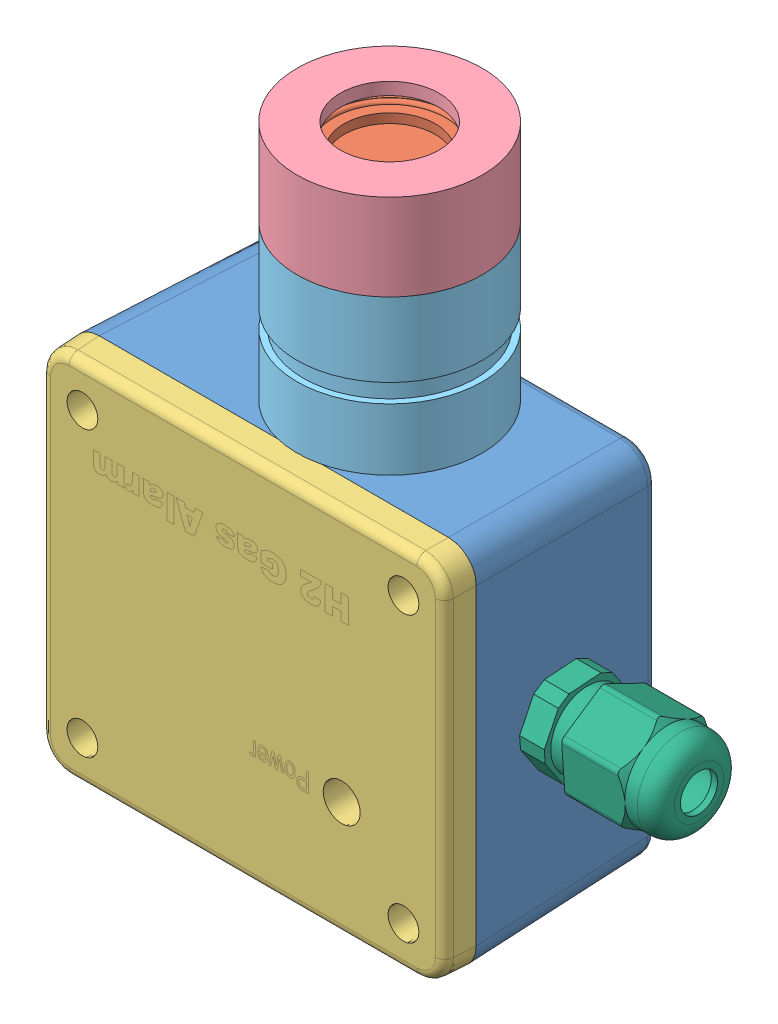
SolidWorks assembly 装配体1, configuration 默认. Lengths in mm.
Overall size (1655.74 254.2 37.77).
239 component instances, 39 part files, 20 mates.
Components (placement in the parent):
- 壳体-1: 壳体 [默认] at (-8.2267 -8.8655 -15.75) size (65.57 59.57 31.5)
- 气体传感器-1: 气体传感器 [默认] at (28.2733 85.2184 -0.0196) x (0.230368 0 0.973104) z (0 -1 0) size (23.5 23.5 30)
- 上盖-1: 上盖 [默认] at (-9.0112 49.9189 19.25) x (1 0 0) z (0 0 -1) size (1633.92 254.2 5.13)
- 传感器顶盖-1: 传感器顶盖 [默认] at (28.2733 89.2184 -0.0196) x (-0.96269 0 -0.270608) z (-0.270608 0 0.96269) size (30 14 30)
- 传感器外壳-1: 传感器外壳 [默认] at (28.2733 80.2184 -0.0196) x (-0.983101 0 -0.183066) z (-0.183066 0 0.983101) size (30 43 30)
- M12-1: M12 [默认] at (73.3763 20.1345 -0.0196) x (0 0.997541 0.070081) z (-1 0 0) size (15.86 14 27)
- 六角螺柱-1: 六角螺柱 [默认] at (21.8837 58.3069 5.887) x (-0.923728 0 0.383049) z (0 -1 0) size (3.46 3 8)
- 六角螺柱-2: 六角螺柱 [默认] at (36.8926 58.3069 -1.944) x (-0.932012 0 0.362427) z (0 -1 0) size (3.46 3 8)
- 六角螺柱-3: 六角螺柱 [默认] at (19.9913 58.3069 -2.9118) x (-0.923728 0 0.383049) z (0 -1 0) size (3.46 3 8)
- 传感器插座板-2: 传感器插座板 [Default] at (28.3871 58.7184 -0.1146) x (-0.21027 0 -0.977643) z (0 1 0) size (23.52 23.52 6.2)
  - JP2.step-1: JP2.step [Default] at origin size (15.8 14.1 6.2)
    - __________.step-1: __________.step [Default] at (-6.3999 3.7001 0) size (3 3 6.2)
    - __________.step-2: __________.step [Default] at (6.4001 -3.7 0) size (3 3 6.2)
    - __________.step-3: __________.step [Default] at (-6.3999 -3.6999 0) size (3 3 6.2)
    - __________.step-4: __________.step [Default] at (6.4001 3.7001 0) size (3 3 6.2)
    - __________.step-5: __________.step [Default] at (0.0001 7.4001 0) size (3 3 6.2)
  - Board^传感器插座板-1: Board^传感器插座板 [Default] at (0 0 -0.4115) size (23.52 23.52 0.41) (virtual)
- 传感器电路板-1: 传感器电路板 [默认] at (25.0182 19.4047 -5.8385) x (-1 -0.00061 0) z (0 0 1) size (52.02 47.02 9.61)
  - 传感器电路板.step-1: 传感器电路板.step [Default] at origin size (52.02 47.02 9.61)
    - U3.step-1: U3.step [Default] at origin size (8.7 6.01 1.9)
      - SOP14.step-1: SOP14.step [Default] at (4.699 -2.54 0) x (0 1 0) z (0 0 1) size (6.01 8.7 1.9)
        - LOGO__0.25.step-1: LOGO__0.25.step [Default] at (0.0116 0 0.095) x (0 -1 0) z (0 0 -1) size (0.75 0.87 0.01)
        - SOP14_____.step-1: SOP14_____.step [Default] at origin size (3.6 8.7 1.8)
        - ____1.8_______.step-1: ____1.8_______.step [Default] at (1.8 3.84 1) x (0 1 0) z (0 0 1) size (0.5 1.2 1.1)
        - ____1.8_______.step-2: ____1.8_______.step [Default] at (1.8 2.57 1) x (0 1 0) z (0 0 1) size (0.5 1.2 1.1)
        - ____1.8_______.step-3: ____1.8_______.step [Default] at (1.8 1.3 1) x (0 1 0) z (0 0 1) size (0.5 1.2 1.1)
        - ____1.8_______.step-4: ____1.8_______.step [Default] at (1.8 0.03 1) x (0 1 0) z (0 0 1) size (0.5 1.2 1.1)
        - ____1.8_______.step-5: ____1.8_______.step [Default] at (1.8 -1.24 1) x (0 1 0) z (0 0 1) size (0.5 1.2 1.1)
        - ____1.8_______.step-6: ____1.8_______.step [Default] at (1.8 -2.51 1) x (0 1 0) z (0 0 1) size (0.5 1.2 1.1)
        - ____1.8_______.step-7: ____1.8_______.step [Default] at (1.8 -3.78 1) x (0 1 0) z (0 0 1) size (0.5 1.2 1.1)
        - ____1.8_______.step-8: ____1.8_______.step [Default] at (-1.8 3.84 1) x (0 -1 0) z (0 0 1) size (0.5 1.2 1.1)
        - ____1.8_______.step-9: ____1.8_______.step [Default] at (-1.8 2.57 1) x (0 -1 0) z (0 0 1) size (0.5 1.2 1.1)
        - ____1.8_______.step-10: ____1.8_______.step [Default] at (-1.8 1.3 1) x (0 -1 0) z (0 0 1) size (0.5 1.2 1.1)
        - ____1.8_______.step-11: ____1.8_______.step [Default] at (-1.8 0.03 1) x (0 -1 0) z (0 0 1) size (0.5 1.2 1.1)
        - ____1.8_______.step-12: ____1.8_______.step [Default] at (-1.8 -1.24 1) x (0 -1 0) z (0 0 1) size (0.5 1.2 1.1)
        - ____1.8_______.step-13: ____1.8_______.step [Default] at (-1.8 -2.51 1) x (0 -1 0) z (0 0 1) size (0.5 1.2 1.1)
        - ____1.8_______.step-14: ____1.8_______.step [Default] at (-1.8 -3.78 1) x (0 -1 0) z (0 0 1) size (0.5 1.2 1.1)
    - U2.step-1: U2.step [Default] at origin size (2.81 3 1.18)
      - SOT23-6.step-1: SOT23-6.step [Default] at (-12.954 7.493 0) x (0 -1 0) z (0 0 1) size (3 2.81 1.18)
        - SOT23-5and6_____.step-1: SOT23-5and6_____.step [Default] at (-0.95 -0.8 0.675) x (-1 0 0) z (0 0 1) size (0.4 0.6 0.78)
        - SOT23-5and6_____.step-2: SOT23-5and6_____.step [Default] at (0 -0.8 0.675) x (-1 0 0) z (0 0 1) size (0.4 0.6 0.78)
        - SOT23-5and6_____.step-3: SOT23-5and6_____.step [Default] at (0.95 -0.8 0.675) x (-1 0 0) z (0 0 1) size (0.4 0.6 0.78)
        - SOT23-5and6_____.step-4: SOT23-5and6_____.step [Default] at (-0.95 0.8 0.675) size (0.4 0.6 0.78)
        - SOT23-5and6_____.step-5: SOT23-5and6_____.step [Default] at (0.95 0.8 0.675) size (0.4 0.6 0.78)
        - LOGO__0.15.step-1: LOGO__0.15.step [Default] at (0 -0.0167 0.0485) x (-1 0 0) z (0 0 -1) size (0.45 0.52 0)
        - SOT23-6-0.step-1: SOT23-6-0.step [Default] at origin size (3 1.6 1.1)
        - SOT23-5and6_____.step-6: SOT23-5and6_____.step [Default] at (0 0.8 0.675) size (0.4 0.6 0.78)
    - U1.step-1: U1.step [Default] at origin size (3 2.81 1.18)
      - SOT23-6.step-1: SOT23-6.step [Default] at (-13.589 -8.636 0) x (-1 0 0) z (0 0 1) size (3 2.81 1.18)
        - SOT23-5and6_____.step-1: SOT23-5and6_____.step [Default] at (-0.95 -0.8 0.675) x (-1 0 0) z (0 0 1) size (0.4 0.6 0.78)
        - SOT23-5and6_____.step-2: SOT23-5and6_____.step [Default] at (0 -0.8 0.675) x (-1 0 0) z (0 0 1) size (0.4 0.6 0.78)
        - SOT23-5and6_____.step-3: SOT23-5and6_____.step [Default] at (0.95 -0.8 0.675) x (-1 0 0) z (0 0 1) size (0.4 0.6 0.78)
        - SOT23-5and6_____.step-4: SOT23-5and6_____.step [Default] at (-0.95 0.8 0.675) size (0.4 0.6 0.78)
        - SOT23-5and6_____.step-5: SOT23-5and6_____.step [Default] at (0.95 0.8 0.675) size (0.4 0.6 0.78)
        - LOGO__0.15.step-1: LOGO__0.15.step [Default] at (0 -0.0167 0.0485) x (-1 0 0) z (0 0 -1) size (0.45 0.52 0)
        - SOT23-6-0.step-1: SOT23-6-0.step [Default] at origin size (3 1.6 1.1)
        - SOT23-5and6_____.step-6: SOT23-5and6_____.step [Default] at (0 0.8 0.675) size (0.4 0.6 0.78)
    - R18.step-1: R18.step [Default] at origin size (1.6 0.8 0.4)
      - R_0603.step-1: R_0603.step [Default] at (-2.667 -1.524 0) x (1 0 0) z (0 0 1) size (1.6 0.8 0.4)
        - R_0603-1.step-1: R_0603-1.step [Default] at origin size (1.6 0.8 0.4)
        - LOGO__.step-1: LOGO__.step [Default] at (0.0001 0.0322 -0.0016) x (-1 0 0) z (0 0 -1) size (0.48 0.55 0)
    - R17.step-1: R17.step [Default] at origin size (0.8 1.6 0.4)
      - R_0603.step-1: R_0603.step [Default] at (5.588 6.858 0) x (0 1 0) z (0 0 1) size (1.6 0.8 0.4)
        - R_0603-1.step-1: R_0603-1.step [Default] at origin size (1.6 0.8 0.4)
        - LOGO__.step-1: LOGO__.step [Default] at (0.0001 0.0322 -0.0016) x (-1 0 0) z (0 0 -1) size (0.48 0.55 0)
    - R16.step-1: R16.step [Default] at origin size (1.6 0.8 0.4)
      - R_0603.step-1: R_0603.step [Default] at (5.461 2.921 0) x (1 0 0) z (0 0 1) size (1.6 0.8 0.4)
        - R_0603-1.step-1: R_0603-1.step [Default] at origin size (1.6 0.8 0.4)
        - LOGO__.step-1: LOGO__.step [Default] at (0.0001 0.0322 -0.0016) x (-1 0 0) z (0 0 -1) size (0.48 0.55 0)
    - R15.step-1: R15.step [Default] at origin size (1.6 0.8 0.4)
      - R_0603.step-1: R_0603.step [Default] at (1.524 2.921 0) x (1 0 0) z (0 0 1) size (1.6 0.8 0.4)
        - R_0603-1.step-1: R_0603-1.step [Default] at origin size (1.6 0.8 0.4)
        - LOGO__.step-1: LOGO__.step [Default] at (0.0001 0.0322 -0.0016) x (-1 0 0) z (0 0 -1) size (0.48 0.55 0)
    - R14.step-1: R14.step [Default] at origin size (1.6 0.8 0.4)
      - R_0603.step-1: R_0603.step [Default] at (7.493 -9.398 0) x (1 0 0) z (0 0 1) size (1.6 0.8 0.4)
        - R_0603-1.step-1: R_0603-1.step [Default] at origin size (1.6 0.8 0.4)
        - LOGO__.step-1: LOGO__.step [Default] at (0.0001 0.0322 -0.0016) x (-1 0 0) z (0 0 -1) size (0.48 0.55 0)
    - R13.step-1: R13.step [Default] at origin size (0.8 1.6 0.4)
      - R_0603.step-1: R_0603.step [Default] at (10.16 -4.699 0) x (0 1 0) z (0 0 1) size (1.6 0.8 0.4)
        - R_0603-1.step-1: R_0603-1.step [Default] at origin size (1.6 0.8 0.4)
        - LOGO__.step-1: LOGO__.step [Default] at (0.0001 0.0322 -0.0016) x (-1 0 0) z (0 0 -1) size (0.48 0.55 0)
    - R12.step-1: R12.step [Default] at origin size (0.8 1.6 0.4)
      - R_0603.step-1: R_0603.step [Default] at (11.811 -4.699 0) x (0 -1 0) z (0 0 1) size (1.6 0.8 0.4)
        - R_0603-1.step-1: R_0603-1.step [Default] at origin size (1.6 0.8 0.4)
        - LOGO__.step-1: LOGO__.step [Default] at (0.0001 0.0322 -0.0016) x (-1 0 0) z (0 0 -1) size (0.48 0.55 0)
    - R11.step-1: R11.step [Default] at origin size (1.6 0.8 0.4)
      - R_0603.step-1: R_0603.step [Default] at (-2.667 -5.715 0) x (1 0 0) z (0 0 1) size (1.6 0.8 0.4)
        - R_0603-1.step-1: R_0603-1.step [Default] at origin size (1.6 0.8 0.4)
        - LOGO__.step-1: LOGO__.step [Default] at (0.0001 0.0322 -0.0016) x (-1 0 0) z (0 0 -1) size (0.48 0.55 0)
    - R10.step-1: R10.step [Default] at origin size (0.8 1.6 0.4)
      - R_0603.step-1: R_0603.step [Default] at (13.462 -4.699 0) x (0 -1 0) z (0 0 1) size (1.6 0.8 0.4)
        - R_0603-1.step-1: R_0603-1.step [Default] at origin size (1.6 0.8 0.4)
        - LOGO__.step-1: LOGO__.step [Default] at (0.0001 0.0322 -0.0016) x (-1 0 0) z (0 0 -1) size (0.48 0.55 0)
    - R9.step-1: R9.step [Default] at origin size (1.6 0.8 0.4)
      - R_0603.step-1: R_0603.step [Default] at (1.524 -9.398 0) x (1 0 0) z (0 0 1) size (1.6 0.8 0.4)
        - R_0603-1.step-1: R_0603-1.step [Default] at origin size (1.6 0.8 0.4)
        - LOGO__.step-1: LOGO__.step [Default] at (0.0001 0.0322 -0.0016) x (-1 0 0) z (0 0 -1) size (0.48 0.55 0)
    - R8.step-1: R8.step [Default] at origin size (0.8 1.6 0.4)
      - R_0603.step-1: R_0603.step [Default] at (16.891 -4.699 0) x (0 1 0) z (0 0 1) size (1.6 0.8 0.4)
        - R_0603-1.step-1: R_0603-1.step [Default] at origin size (1.6 0.8 0.4)
        - LOGO__.step-1: LOGO__.step [Default] at (0.0001 0.0322 -0.0016) x (-1 0 0) z (0 0 -1) size (0.48 0.55 0)
    - R7.step-1: R7.step [Default] at origin size (0.8 1.6 0.4)
      - R_0603.step-1: R_0603.step [Default] at (15.24 -4.699 0) x (0 1 0) z (0 0 1) size (1.6 0.8 0.4)
        - R_0603-1.step-1: R_0603-1.step [Default] at origin size (1.6 0.8 0.4)
        - LOGO__.step-1: LOGO__.step [Default] at (0.0001 0.0322 -0.0016) x (-1 0 0) z (0 0 -1) size (0.48 0.55 0)
    - R6.step-1: R6.step [Default] at origin size (0.8 1.6 0.4)
      - R_0603.step-1: R_0603.step [Default] at (-14.605 3.81 0) x (0 -1 0) z (0 0 1) size (1.6 0.8 0.4)
        - R_0603-1.step-1: R_0603-1.step [Default] at origin size (1.6 0.8 0.4)
        - LOGO__.step-1: LOGO__.step [Default] at (0.0001 0.0322 -0.0016) x (-1 0 0) z (0 0 -1) size (0.48 0.55 0)
    - R5.step-1: R5.step [Default] at origin size (0.8 1.6 0.4)
      - R_0603.step-1: R_0603.step [Default] at (-12.954 3.81 0) x (0 -1 0) z (0 0 1) size (1.6 0.8 0.4)
        - R_0603-1.step-1: R_0603-1.step [Default] at origin size (1.6 0.8 0.4)
        - LOGO__.step-1: LOGO__.step [Default] at (0.0001 0.0322 -0.0016) x (-1 0 0) z (0 0 -1) size (0.48 0.55 0)
    - R4.step-1: R4.step [Default] at origin size (0.8 1.6 0.4)
      - R_0603.step-1: R_0603.step [Default] at (-11.303 3.81 0) x (0 -1 0) z (0 0 1) size (1.6 0.8 0.4)
        - R_0603-1.step-1: R_0603-1.step [Default] at origin size (1.6 0.8 0.4)
        - LOGO__.step-1: LOGO__.step [Default] at (0.0001 0.0322 -0.0016) x (-1 0 0) z (0 0 -1) size (0.48 0.55 0)
    - R3.step-1: R3.step [Default] at origin size (1.6 0.8 0.4)
      - R_0603.step-1: R_0603.step [Default] at (-16.256 -5.969 -0.4115) x (1 0 0) z (0 0 -1) size (1.6 0.8 0.4)
        - R_0603-1.step-1: R_0603-1.step [Default] at origin size (1.6 0.8 0.4)
        - LOGO__.step-1: LOGO__.step [Default] at (0.0001 0.0322 -0.0016) x (-1 0 0) z (0 0 -1) size (0.48 0.55 0)
    - R2.step-1: R2.step [Default] at origin size (1.6 0.8 0.4)
      - R_0603.step-1: R_0603.step [Default] at (-16.256 -7.747 -0.4115) x (1 0 0) z (0 0 -1) size (1.6 0.8 0.4)
        - R_0603-1.step-1: R_0603-1.step [Default] at origin size (1.6 0.8 0.4)
        - LOGO__.step-1: LOGO__.step [Default] at (0.0001 0.0322 -0.0016) x (-1 0 0) z (0 0 -1) size (0.48 0.55 0)
    - R1.step-1: R1.step [Default] at origin size (1.6 0.8 0.4)
      - R_0603.step-1: R_0603.step [Default] at (-16.256 -9.652 -0.4115) x (-1 0 0) z (0 0 -1) size (1.6 0.8 0.4)
        - R_0603-1.step-1: R_0603-1.step [Default] at origin size (1.6 0.8 0.4)
        - LOGO__.step-1: LOGO__.step [Default] at (0.0001 0.0322 -0.0016) x (-1 0 0) z (0 0 -1) size (0.48 0.55 0)
    - Q2.step-1: Q2.step [Default] at origin size (2.4 3 1.05)
      - SOT23-3.step-1: SOT23-3.step [Default] at (15.24 -8.382 0) x (0 -1 0) z (0 0 1) size (3 2.4 1.05)
        - SOT23-3-2.step-1: SOT23-3-2.step [Default] at origin size (3 1.3 1)
        - SOT23-3_____.step-1: SOT23-3_____.step [Default] at (0 0.5461 0.475) size (0.4 0.65 0.55)
        - SOT23-3_____.step-2: SOT23-3_____.step [Default] at (-0.95 -0.5461 0.475) x (-1 0 0) z (0 0 1) size (0.4 0.65 0.55)
        - SOT23-3_____.step-3: SOT23-3_____.step [Default] at (0.95 -0.5461 0.475) x (-1 0 0) z (0 0 1) size (0.4 0.65 0.55)
        - LOGO__0.15-3.step-1: LOGO__0.15-3.step [Default] at (0 -0.0163 0.0485) x (-1 0 0) z (0 0 -1) size (0.45 0.52 0)
    - Q1.step-1: Q1.step [Default] at origin size (2.4 3 1.05)
      - SOT23-3.step-1: SOT23-3.step [Default] at (-5.334 -8.509 0) x (0 1 0) z (0 0 1) size (3 2.4 1.05)
        - SOT23-3-2.step-1: SOT23-3-2.step [Default] at origin size (3 1.3 1)
        - SOT23-3_____.step-1: SOT23-3_____.step [Default] at (0 0.5461 0.475) size (0.4 0.65 0.55)
        - SOT23-3_____.step-2: SOT23-3_____.step [Default] at (-0.95 -0.5461 0.475) x (-1 0 0) z (0 0 1) size (0.4 0.65 0.55)
        - SOT23-3_____.step-3: SOT23-3_____.step [Default] at (0.95 -0.5461 0.475) x (-1 0 0) z (0 0 1) size (0.4 0.65 0.55)
        - LOGO__0.15-3.step-1: LOGO__0.15-3.step [Default] at (0 -0.0163 0.0485) x (-1 0 0) z (0 0 -1) size (0.45 0.52 0)
    - P2.step-1: P2.step [Default] at origin size (5.7 15.16 9.5)
      - XH2.54-5P.step-1: XH2.54-5P.step [Default] at (22.098 -1.524 0.03) x (0 1 0) z (1 0 0) size (15.16 9.5 5.7)
        - LOGO__-4.step-1: LOGO__-4.step [Default] at (-1.7013 -0.001 0) x (0 0 1) z (0 -1 0) size (0.9 1.04 0.01)
        - XH2.54-5P-5.step-1: XH2.54-5P-5.step [Default] at origin size (15.16 9.5 5.7)
    - L2.step-1: L2.step [Default] at origin size (6.6 6.95 3.03)
      - SMD-0630.step-1: SMD-0630.step [Default] at (-19.304 5.207 0) x (0 -1 0) z (0 0 1) size (6.95 6.6 3.03)
        - SMD-0630-6.step-1: SMD-0630-6.step [Default] at origin size (6.95 6.6 3.03)
        - LOGO__0.5.step-1: LOGO__0.5.step [Default] at (0 0.0017 0.04) size (1.5 1.73 0.01)
    - L1.step-1: L1.step [Default] at origin size (6.6 6.95 3.03)
      - SMD-0630.step-1: SMD-0630.step [Default] at (-19.05 -7.239 0) x (0 1 0) z (0 0 1) size (6.95 6.6 3.03)
        - SMD-0630-6.step-1: SMD-0630-6.step [Default] at origin size (6.95 6.6 3.03)
        - LOGO__0.5.step-1: LOGO__0.5.step [Default] at (0 0.0017 0.04) size (1.5 1.73 0.01)
    - D8.step-1: D8.step [Default] at origin size (5.12 2.6 2.11)
      - SMA.step-1: SMA.step [Default] at (-19.0271 4.9529 -0.4615) x (-1 0 0) z (0 0 -1) size (5.12 2.6 2.11)
        - SMA-7.step-1: SMA-7.step [Default] at origin size (5.12 2.6 2.1)
        - LOGO______.__.step-1: LOGO______.__.step [Default] at (0.0018 0.0048 -0.003) x (-1 0 0) z (0 0 -1) size (0.9 1.04 0.01)
    - D7.step-1: D7.step [Default] at origin size (2.6 5.12 2.11)
      - SMA.step-1: SMA.step [Default] at (-22.4789 -7.2161 -0.4615) x (0 -1 0) z (0 0 -1) size (5.12 2.6 2.11)
        - SMA-7.step-1: SMA-7.step [Default] at origin size (5.12 2.6 2.1)
        - LOGO______.__.step-1: LOGO______.__.step [Default] at (0.0018 0.0048 -0.003) x (-1 0 0) z (0 0 -1) size (0.9 1.04 0.01)
    - D6.step-1: D6.step [Default] at origin size (5.31 3.6 2.31)
      - SMB.step-1: SMB.step [Default] at (13.0581 5.5879 0.05) x (1 0 0) z (0 0 1) size (5.31 3.6 2.31)
        - SMB-8.step-1: SMB-8.step [Default] at origin size (5.31 3.6 2.3)
        - LOGO______.__-9.step-1: LOGO______.__-9.step [Default] at (-0.0044 0 -0.003) x (-1 0 0) z (0 0 -1) size (0.9 1.04 0.01)
    - D5.step-1: D5.step [Default] at origin size (3.7 1.6 1.27)
      - SOD123.step-1: SOD123.step [Default] at (-3.5309 -11.6339 0) x (1 0 0) z (0 -1 0) size (3.7 1.27 1.6)
    - D4.step-1: D4.step [Default] at origin size (5.12 2.6 2.11)
      - SMA.step-1: SMA.step [Default] at (12.0421 -11.9381 0.05) x (1 0 0) z (0 0 1) size (5.12 2.6 2.11)
        - SMA-7.step-1: SMA-7.step [Default] at origin size (5.12 2.6 2.1)
        - LOGO______.__.step-1: LOGO______.__.step [Default] at (0.0018 0.0048 -0.003) x (-1 0 0) z (0 0 -1) size (0.9 1.04 0.01)
    - D3.step-1: D3.step [Default] at origin size (5.12 2.6 2.11)
      - SMA.step-1: SMA.step [Default] at (4.9759 -11.9379 0.05) x (-1 0 0) z (0 0 1) size (5.12 2.6 2.11)
        - SMA-7.step-1: SMA-7.step [Default] at origin size (5.12 2.6 2.1)
        - LOGO______.__.step-1: LOGO______.__.step [Default] at (0.0018 0.0048 -0.003) x (-1 0 0) z (0 0 -1) size (0.9 1.04 0.01)
    - D2.step-1: D2.step [Default] at origin size (3.6 5.31 2.31)
      - SMB.step-1: SMB.step [Default] at (17.1449 11.8339 0.05) x (0 -1 0) z (0 0 1) size (5.31 3.6 2.31)
        - SMB-8.step-1: SMB-8.step [Default] at origin size (5.31 3.6 2.3)
        - LOGO______.__-9.step-1: LOGO______.__-9.step [Default] at (-0.0044 0 -0.003) x (-1 0 0) z (0 0 -1) size (0.9 1.04 0.01)
    - D1.step-1: D1.step [Default] at origin size (2.6 5.12 2.11)
      - SMA.step-1: SMA.step [Default] at (13.3349 11.9609 0.05) x (0 -1 0) z (0 0 1) size (5.12 2.6 2.11)
        - SMA-7.step-1: SMA-7.step [Default] at origin size (5.12 2.6 2.1)
        - LOGO______.__.step-1: LOGO______.__.step [Default] at (0.0018 0.0048 -0.003) x (-1 0 0) z (0 0 -1) size (0.9 1.04 0.01)
    - C10.step-1: C10.step [Default] at origin size (1.6 0.82 0.82)
      - C_0603.step-1: C_0603.step [Default] at (7.493 -7.62 0) x (-1 0 0) z (0 0 1) size (1.6 0.82 0.82)
        - LOGO__-10.step-1: LOGO__-10.step [Default] at (0 0.0171 -0.0006) x (-1 0 0) z (0 0 -1) size (0.51 0.59 0)
        - C_0603-11.step-1: C_0603-11.step [Default] at origin size (1.6 0.82 0.82)
    - C9.step-1: C9.step [Default] at origin size (1.6 0.82 0.82)
      - C_0603.step-1: C_0603.step [Default] at (1.524 -7.62 0) x (1 0 0) z (0 0 1) size (1.6 0.82 0.82)
        - LOGO__-10.step-1: LOGO__-10.step [Default] at (0 0.0171 -0.0006) x (-1 0 0) z (0 0 -1) size (0.51 0.59 0)
        - C_0603-11.step-1: C_0603-11.step [Default] at origin size (1.6 0.82 0.82)
    - C8.step-1: C8.step [Default] at origin size (3.2 1.62 1.22)
      - C_1206.step-1: C_1206.step [Default] at (-19.558 1.778 -0.4115) x (1 0 0) z (0 0 -1) size (3.2 1.62 1.22)
        - LOGO__-12.step-1: LOGO__-12.step [Default] at (0 0.0171 -0.0006) x (-1 0 0) z (0 0 -1) size (0.51 0.59 0)
        - C_1206-13.step-1: C_1206-13.step [Default] at origin size (3.2 1.62 1.22)
    - C7.step-1: C7.step [Default] at origin size (1.62 3.2 1.22)
      - C_1206.step-1: C_1206.step [Default] at (-19.431 -7.874 -0.4115) x (0 -1 0) z (0 0 -1) size (3.2 1.62 1.22)
        - LOGO__-12.step-1: LOGO__-12.step [Default] at (0 0.0171 -0.0006) x (-1 0 0) z (0 0 -1) size (0.51 0.59 0)
        - C_1206-13.step-1: C_1206-13.step [Default] at origin size (3.2 1.62 1.22)
    - C6.step-1: C6.step [Default] at origin size (3.2 1.62 1.22)
      - C_1206.step-1: C_1206.step [Default] at (12.319 2.286 0) x (-1 0 0) z (0 0 1) size (3.2 1.62 1.22)
        - LOGO__-12.step-1: LOGO__-12.step [Default] at (0 0.0171 -0.0006) x (-1 0 0) z (0 0 -1) size (0.51 0.59 0)
        - C_1206-13.step-1: C_1206-13.step [Default] at origin size (3.2 1.62 1.22)
    - C5.step-1: C5.step [Default] at origin size (1.6 0.82 0.82)
      - C_0603.step-1: C_0603.step [Default] at (-12.573 10.16 0) x (1 0 0) z (0 0 1) size (1.6 0.82 0.82)
        - LOGO__-10.step-1: LOGO__-10.step [Default] at (0 0.0171 -0.0006) x (-1 0 0) z (0 0 -1) size (0.51 0.59 0)
        - C_0603-11.step-1: C_0603-11.step [Default] at origin size (1.6 0.82 0.82)
    - C4.step-1: C4.step [Default] at origin size (1.62 3.2 1.22)
      - C_1206.step-1: C_1206.step [Default] at (18.923 7.493 -0.4115) x (0 -1 0) z (0 0 -1) size (3.2 1.62 1.22)
        - LOGO__-12.step-1: LOGO__-12.step [Default] at (0 0.0171 -0.0006) x (-1 0 0) z (0 0 -1) size (0.51 0.59 0)
        - C_1206-13.step-1: C_1206-13.step [Default] at origin size (3.2 1.62 1.22)
    - C3.step-1: C3.step [Default] at origin size (3.2 1.62 1.22)
      - C_1206.step-1: C_1206.step [Default] at (-19.685 8.128 -0.4115) x (-1 0 0) z (0 0 -1) size (3.2 1.62 1.22)
        - LOGO__-12.step-1: LOGO__-12.step [Default] at (0 0.0171 -0.0006) x (-1 0 0) z (0 0 -1) size (0.51 0.59 0)
        - C_1206-13.step-1: C_1206-13.step [Default] at origin size (3.2 1.62 1.22)
    - C2.step-1: C2.step [Default] at origin size (3.2 1.62 1.22)
      - C_1206.step-1: C_1206.step [Default] at (-19.685 11.049 -0.4115) x (-1 0 0) z (0 0 -1) size (3.2 1.62 1.22)
        - LOGO__-12.step-1: LOGO__-12.step [Default] at (0 0.0171 -0.0006) x (-1 0 0) z (0 0 -1) size (0.51 0.59 0)
        - C_1206-13.step-1: C_1206-13.step [Default] at origin size (3.2 1.62 1.22)
    - C1.step-1: C1.step [Default] at origin size (1.6 0.82 0.82)
      - C_0603.step-1: C_0603.step [Default] at (-13.1699 -4.445 0) x (-1 0 0) z (0 0 1) size (1.6 0.82 0.82)
        - LOGO__-10.step-1: LOGO__-10.step [Default] at (0 0.0171 -0.0006) x (-1 0 0) z (0 0 -1) size (0.51 0.59 0)
        - C_0603-11.step-1: C_0603-11.step [Default] at origin size (1.6 0.82 0.82)
    - LED1.step-1: LED1.step [Default] at origin size (1.25 2 0.81)
      - LED_0805-R.step-1: LED_0805-R.step [Default] at (-6.604 13.716 0) x (0 -1 0) z (0 0 1) size (2 1.25 0.67)
        - LOGO__-14.step-1: LOGO__-14.step [Default] at (0 0.0303 -0.002) x (-1 0 0) z (0 0 -1) size (0.6 0.69 0)
        - LED_0805-R-15.step-1: LED_0805-R-15.step [Default] at origin size (2 1.25 0.67)
      - LED_0805______.step-1: LED_0805______.step [Default] at (-6.604 13.716 0) x (0 1 0) z (0 0 1) size (1.5 1.25 0.5)
    - R19.step-1: R19.step [Default] at origin size (1.6 0.8 0.4)
      - R_0603.step-1: R_0603.step [Default] at (-1.651 16.256 -0.4115) x (-1 0 0) z (0 0 -1) size (1.6 0.8 0.4)
        - R_0603-1.step-1: R_0603-1.step [Default] at origin size (1.6 0.8 0.4)
        - LOGO__.step-1: LOGO__.step [Default] at (0.0001 0.0322 -0.0016) x (-1 0 0) z (0 0 -1) size (0.48 0.55 0)
    - P4.step-1: P4.step [Default] at origin size (7.54 5.7 9.5)
      - XH2.54-2P.step-1: XH2.54-2P.step [Default] at (6.223 11.557 0.05) x (-1 0 0) z (0 1 0) size (7.54 9.5 5.7)
        - XH2.54-2P-16.step-1: XH2.54-2P-16.step [Default] at origin size (7.54 9.5 5.7)
        - LOGO__-17.step-1: LOGO__-17.step [Default] at (-1.7013 -0.001 0) x (0 0 1) z (0 -1 0) size (0.9 1.04 0.01)
    - Board.step-1: Board.step [Default] at (0 0 -0.4115) size (52.02 47.02 0.41)
Mates (geometry in assembly coordinates):
- 重合5: coincident anti-aligned: plane of 壳体-1 through (-8.2267 -8.8655 14.25) normal (0 0 1); plane of 上盖-1 through (-9.0112 49.9189 14.25) normal (0 0 -1)
- 重合6: coincident anti-aligned: line of 壳体-1 through (-4.5139 -9.6511 14.25) axis (1 0 0); line of 上盖-1 through (52.0616 -9.6511 14.25) axis (-1 0 0)
- 重合7: coincident anti-aligned: line of 壳体-1 through (56.5588 -5.1526 14.25) axis (0 1 0); line of 上盖-1 through (56.5588 45.4217 14.25) axis (0 -1 0)
- 同心1: concentric aligned: cylinder of 气体传感器-1 through (28.2733 60.7184 -0.0196) axis (0 1 0) radius 11.75; cylinder of 传感器外壳-1 through (28.2733 80.2184 -0.0196) axis (0 1 0) radius 12
- 同心2: concentric aligned: cylinder of 气体传感器-1 through (28.2733 60.7184 -0.0196) axis (0 1 0) radius 11.75; cylinder of 传感器顶盖-1 through (28.2733 89.2184 -0.0196) axis (0 1 0) radius 13.5
- 重合8: coincident anti-aligned: plane of 气体传感器-1 through (28.2733 85.2184 -0.0196) normal (0 1 0); plane of 传感器顶盖-1 through (16.721 85.2184 -3.2669) normal (0 -1 0)
- 螺旋1: screw = 1.5 aligned: cylinder of 壳体-1 through (28.2733 49.9201 -0.0196) axis (0 1 0) radius 9.25; cylinder of 传感器外壳-1 through (28.2733 80.2184 -0.0196) axis (0 1 0) radius 10
- 螺旋3: screw = 1.5 aligned: cylinder of 壳体-1 through (56.5588 20.1345 -0.0196) axis (1 0 0) radius 5.25; cylinder of M12-1 through (51.3763 20.1345 -0.0196) axis (1 0 0) radius 6
- 重合19: coincident anti-aligned: plane of 传感器顶盖-1 through (13.8329 75.2184 -4.0788) normal (0 -1 0); plane of 传感器外壳-1 through (13.5267 75.2184 -2.7656) normal (0 1 0)
- 同心3: concentric aligned: cylinder of 气体传感器-1 through (33.3501 55.7184 5.3642) axis (0 1 0) radius 0.75; cylinder of 传感器插座板-2/JP2.step-1/__________.step-3 through (33.3501 60.7184 5.3642) axis (0 1 0) radius 0.5
- 重合20: coincident anti-aligned: plane of 气体传感器-1 through (28.2733 60.7184 -0.0196) normal (0 -1 0); plane of 传感器插座板-2/JP2.step-1/__________.step-5 through (21.1525 60.7184 1.4413) normal (0 1 0)
- 锁定1: lock: unknown of 气体传感器-1; unknown of 传感器插座板-2/Board^传感器插座板-1
- 同心6: concentric aligned: cylinder of 六角螺柱-3 through (19.9913 61.3069 -2.9118) axis (0 -1 0) radius 1; cylinder of 传感器插座板-2/Board^传感器插座板-1 through (19.9913 58.3069 -2.9118) axis (0 -1 0) radius 1.1
- 同心7: concentric aligned: cylinder of 六角螺柱-2 through (36.8926 61.3069 -1.944) axis (0 -1 0) radius 1; cylinder of 传感器插座板-2/Board^传感器插座板-1 through (36.8926 58.3069 -1.944) axis (0 -1 0) radius 1.1
- 同心8: concentric aligned: cylinder of 六角螺柱-1 through (21.8837 61.3069 5.887) axis (0 -1 0) radius 1; cylinder of 传感器插座板-2/Board^传感器插座板-1 through (21.8837 58.3069 5.887) axis (0 -1 0) radius 1.1
- 重合22: coincident anti-aligned: plane of 六角螺柱-1 through (21.8837 58.3069 5.887) normal (0 1 0); plane of 传感器插座板-2/Board^传感器插座板-1 through (30.8602 58.3069 11.3836) normal (0 -1 0)
- 重合23: coincident anti-aligned: plane of 六角螺柱-3 through (19.9913 58.3069 -2.9118) normal (0 1 0); plane of 传感器插座板-2/Board^传感器插座板-1 through (30.8602 58.3069 11.3836) normal (0 -1 0)
- 重合24: coincident anti-aligned: plane of 六角螺柱-2 through (36.8926 58.3069 -1.944) normal (0 1 0); plane of 传感器插座板-2/Board^传感器插座板-1 through (30.8602 58.3069 11.3836) normal (0 -1 0)
- 距离1: distance = 7 mm anti-aligned: plane of 传感器电路板-1/传感器电路板.step-1/Board.step-1 through (45.0151 40.4169 -6.25) normal (0 0 -1); plane of 壳体-1 through (-8.2267 -8.8655 -13.25) normal (0 0 1)
- 平行1: parallel: line of 壳体-1 through (6.8925 -5.431 -13.25) axis (1 0 0); plane of 传感器电路板-1/传感器电路板.step-1/Board.step-1 through (9.0328 -4.605 -6.25) normal (0 -1 0)
